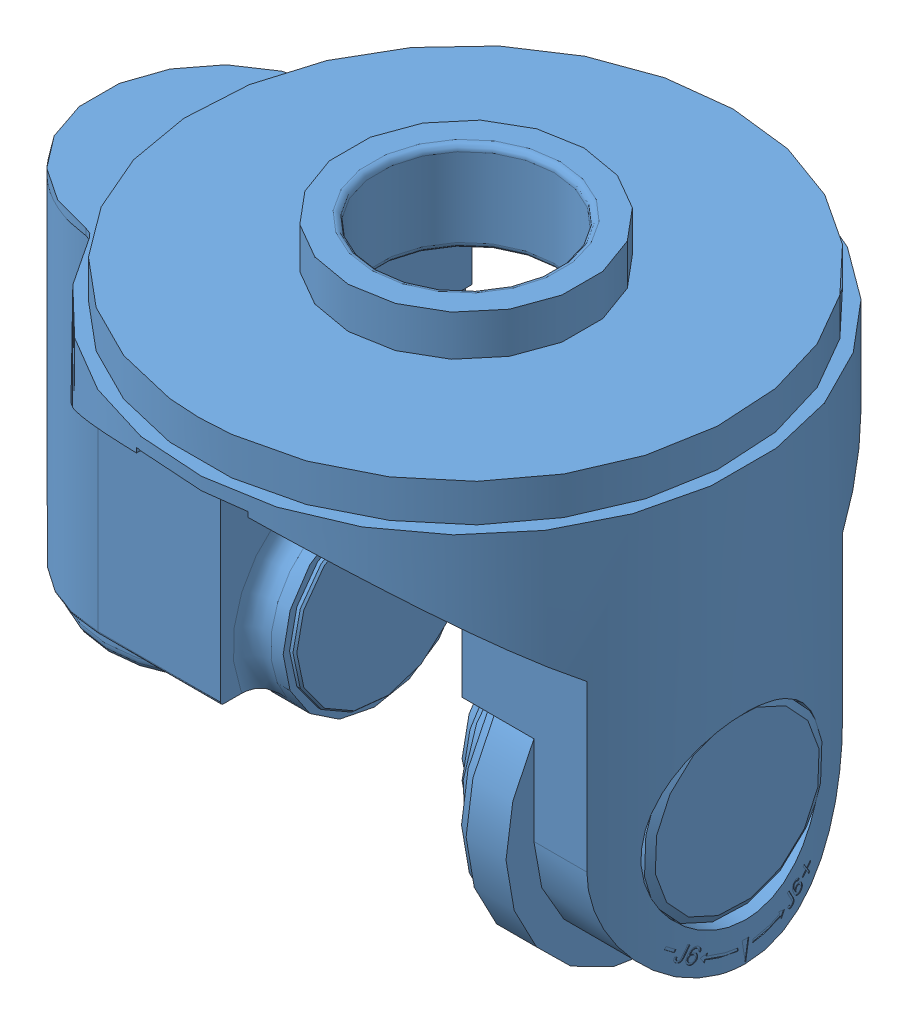
SolidWorks assembly B2716, configuration Default. Lengths in mm.
Overall size (103.08 85.22 88.9).
6 component instances, 3 part files, 3 mates.
Components (placement in the parent):
- B2573-1: B2573 [Default] at origin size (103.08 85.22 88.9)
- B1995-1: B1995 [6] at (0 -47.95 0) x (0 0 1) z (0 1 0) size (239.39 157.62 264.32) (suppressed, hidden)
  - B1998-1: B1998 [X6] x (0 0 -1) z (1 0 0)
  - B1998-2: B1998 [Y6] x (0 0 1) z (0 1 0)
  - B1998-3: B1998 [Z6] at origin
  - B1999-2: B1999 [100] at (0 0 197.2124) x (0 0 -1) z (0.268665 -0.963234 0)
Mates (geometry in assembly coordinates):
- Coincident1: coincident aligned: plane of B1995-1; plane of assembly
- Coincident2: coincident aligned: plane of B1995-1; plane of assembly
- Coincident3: coincident aligned: plane of B1995-1; plane of B2573-1
